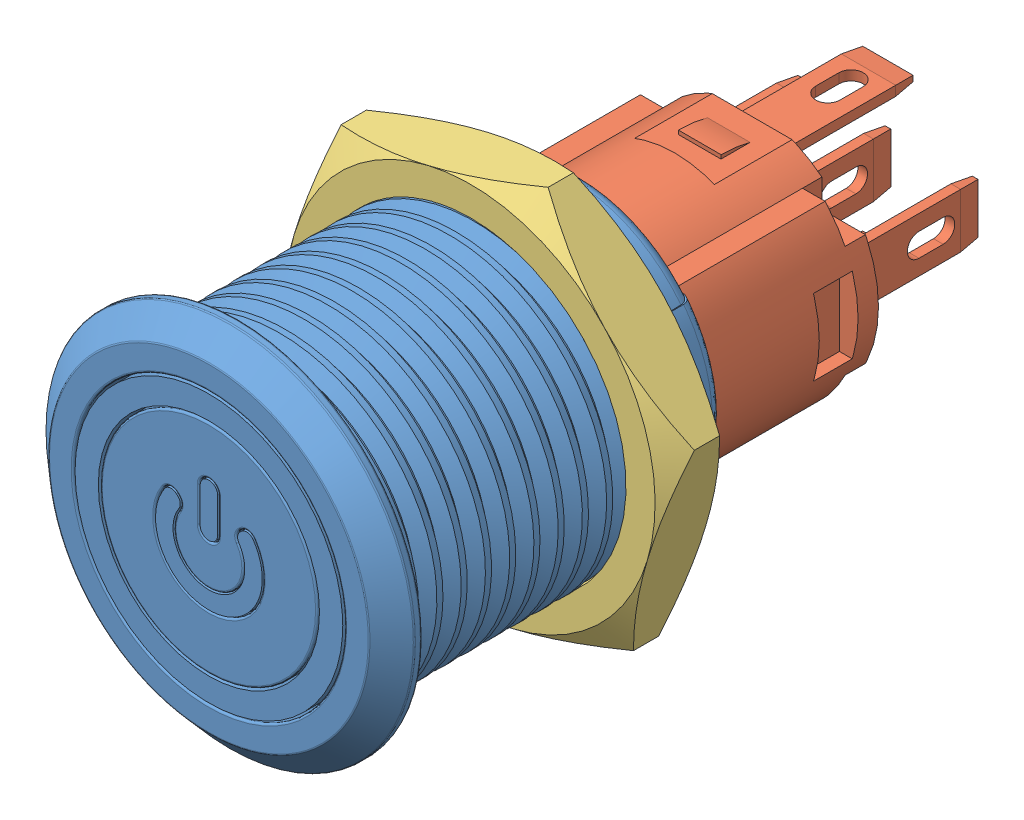
SolidWorks assembly 16mm-LED-Power-Button, configuration Default. Lengths in mm.
Overall size (28.88 29 35).
3 component instances, 3 part files, 2 mates.
Components (placement in the parent):
- Button_Body-1: Button_Body [Default] at origin size (19 19 19.3)
- Socket-1: Socket [Default] at origin size (12.92 12.92 26)
- Hex_Nut_M16-3mm-2: Hex_Nut_M16-3mm [Default] at (0 0 -7.5) x (-0.726686 -0.68697 0) z (0 0 1) size (19 21.94 3.41)
Mates (geometry in assembly coordinates):
- Concentric1: concentric: circle of Hex_Nut_M16-3mm-2; circle of Button_Body-1
- Distance1: distance = 12 mm anti-aligned: plane of Button_Body-1 through (0 0 7.5) normal (0 0 -1); plane of Hex_Nut_M16-3mm-2 through (0 0 -4.5) normal (0 0 1)
